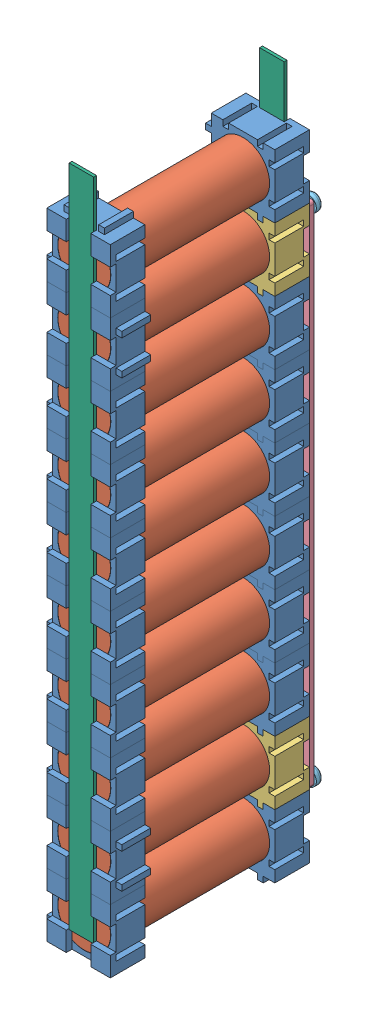
SolidWorks assembly 18650Module, configuration Default. Lengths in mm.
Overall size (26 239.99 73.08).
47 component instances, 6 part files, 28 mates.
Components (placement in the parent):
- BatteryWithCap-1: BatteryWithCap [Default] at (-119.8908 1.6761 1.2883) size (24 26 69)
  - EndCap-1: EndCap [Default] at (-3.9524 14.5628 21.4054) size (24 24 12)
  - HB2-1: HB2 [Default] at (-2.3515 12.807 21.4054) x (1 0 0) z (0 1 0) size (18.3 65.2 18.3)
  - EndCap-2: EndCap [Default] at (-3.9524 11.0511 86.4054) x (1 0 0) z (0 0 -1) size (24 24 12)
- BatteryWithCap-3: BatteryWithCap [Default] at (-119.8908 45.6761 1.2883) size (24 26 69)
  - EndCap-1: EndCap [Default] at (-3.9524 14.5628 21.4054) size (24 24 12)
  - HB2-1: HB2 [Default] at (-2.3515 12.807 21.4054) x (1 0 0) z (0 1 0) size (18.3 65.2 18.3)
  - EndCap-2: EndCap [Default] at (-3.9524 11.0511 86.4054) x (1 0 0) z (0 0 -1) size (24 24 12)
- BatteryWithCap-4: BatteryWithCap [Default] at (-119.8908 67.6761 1.2883) size (24 26 69)
  - EndCap-1: EndCap [Default] at (-3.9524 14.5628 21.4054) size (24 24 12)
  - HB2-1: HB2 [Default] at (-2.3515 12.807 21.4054) x (1 0 0) z (0 1 0) size (18.3 65.2 18.3)
  - EndCap-2: EndCap [Default] at (-3.9524 11.0511 86.4054) x (1 0 0) z (0 0 -1) size (24 24 12)
- BatteryWithCap-5: BatteryWithCap [Default] at (-119.8908 89.6761 1.2883) size (24 26 69)
  - EndCap-1: EndCap [Default] at (-3.9524 14.5628 21.4054) size (24 24 12)
  - HB2-1: HB2 [Default] at (-2.3515 12.807 21.4054) x (1 0 0) z (0 1 0) size (18.3 65.2 18.3)
  - EndCap-2: EndCap [Default] at (-3.9524 11.0511 86.4054) x (1 0 0) z (0 0 -1) size (24 24 12)
- BatteryWithCap-6: BatteryWithCap [Default] at (-119.8908 111.6761 1.2883) size (24 26 69)
  - EndCap-1: EndCap [Default] at (-3.9524 14.5628 21.4054) size (24 24 12)
  - HB2-1: HB2 [Default] at (-2.3515 12.807 21.4054) x (1 0 0) z (0 1 0) size (18.3 65.2 18.3)
  - EndCap-2: EndCap [Default] at (-3.9524 11.0511 86.4054) x (1 0 0) z (0 0 -1) size (24 24 12)
- BatteryWithCap-7: BatteryWithCap [Default] at (-119.8908 133.6761 1.2883) size (24 26 69)
  - EndCap-1: EndCap [Default] at (-3.9524 14.5628 21.4054) size (24 24 12)
  - HB2-1: HB2 [Default] at (-2.3515 12.807 21.4054) x (1 0 0) z (0 1 0) size (18.3 65.2 18.3)
  - EndCap-2: EndCap [Default] at (-3.9524 11.0511 86.4054) x (1 0 0) z (0 0 -1) size (24 24 12)
- BatteryWithCap-8: BatteryWithCap [Default] at (-119.8908 155.6761 1.2883) size (24 26 69)
  - EndCap-1: EndCap [Default] at (-3.9524 14.5628 21.4054) size (24 24 12)
  - HB2-1: HB2 [Default] at (-2.3515 12.807 21.4054) x (1 0 0) z (0 1 0) size (18.3 65.2 18.3)
  - EndCap-2: EndCap [Default] at (-3.9524 11.0511 86.4054) x (1 0 0) z (0 0 -1) size (24 24 12)
- BatteryWithCap-10: BatteryWithCap [Default] at (-119.8908 199.6761 1.2883) size (24 26 69)
  - EndCap-1: EndCap [Default] at (-3.9524 14.5628 21.4054) size (24 24 12)
  - HB2-1: HB2 [Default] at (-2.3515 12.807 21.4054) x (1 0 0) z (0 1 0) size (18.3 65.2 18.3)
  - EndCap-2: EndCap [Default] at (-3.9524 11.0511 86.4054) x (1 0 0) z (0 0 -1) size (24 24 12)
- ModuleWithM3EndCap-1: ModuleWithM3EndCap [Default] at (-93.9861 180.3782 17.4413) size (26 24.96 69)
  - EndCapWithM3-1: EndCapWithM3 [Default] at (-29.8572 11.8608 5.2524) size (24 24 12)
  - HB2-1: HB2 [Default] at (-28.2562 10.1049 70.2524) x (0.923728 0.383049 0) z (0.383049 -0.923728 0) size (18.3 65.2 18.3)
  - EndCap-1: EndCap [Default] at (-26.6553 11.8608 70.2524) x (-1 0 0) z (0 0 -1) size (24 24 12)
- ModuleWithM3EndCap-2: ModuleWithM3EndCap [Default] at (-93.9861 26.3782 17.4413) size (26 24.96 69)
  - EndCapWithM3-1: EndCapWithM3 [Default] at (-29.8572 11.8608 5.2524) size (24 24 12)
  - HB2-1: HB2 [Default] at (-28.2562 10.1049 70.2524) x (0.923728 0.383049 0) z (0.383049 -0.923728 0) size (18.3 65.2 18.3)
  - EndCap-1: EndCap [Default] at (-26.6553 11.8608 70.2524) x (-1 0 0) z (0 0 -1) size (24 24 12)
- DummyPCB-1: DummyPCB [Default] at (-97.7038 122.1138 19.0937) size (22 176 1.6)
- pan slot head_am-1: pan slot head_am [B18.6.7M - M3 x 0.5 x 6 Slotted PHMS --6N] at (-113.2423 27.4831 16.6937) x (0 0 1) z (-1 0 0) size (8.48 5.6 5.6)
- pan slot head_am-2: pan slot head_am [B18.6.7M - M3 x 0.5 x 6 Slotted PHMS --6N] at (-113.2423 199.4831 16.6937) x (0 0 1) z (-0.166536 0.986035 0) size (8.48 5.6 5.6)
- pan slot head_am-3: pan slot head_am [B18.6.7M - M3 x 0.5 x 6 Slotted PHMS --6N] at (-131.2423 199.4831 16.6937) x (0 0 1) z (0.381849 0.924225 0) size (8.48 5.6 5.6)
- pan slot head_am-4: pan slot head_am [B18.6.7M - M3 x 0.5 x 6 Slotted PHMS --6N] at (-131.2423 27.4831 16.6937) x (0 0 1) z (-1 0 0) size (8.48 5.6 5.6)
- CopperConductor-1: CopperConductor [Default] at (-122.6962 224.087 88.6937) size (8.5 230 1)
- CopperConductor-2: CopperConductor [Default] at (-122.6962 225.6736 22.6937) size (8.5 230 1)
Mates (geometry in assembly coordinates):
- Coincident20: coincident aligned: line of BatteryWithCap-3/EndCap-2 through (-133.2423 69.4831 77.6937) axis (0 0 1); line of BatteryWithCap-4/EndCap-2 through (-133.2423 69.4831 77.6937) axis (0 0 1)
- Coincident21: coincident anti-aligned: line of BatteryWithCap-3/EndCap-1 through (-129.2423 67.4831 32.6937) axis (1 0 0); line of BatteryWithCap-4/EndCap-1 through (-127.2423 67.4831 32.6937) axis (-1 0 0)
- Coincident22: coincident aligned: line of BatteryWithCap-4/EndCap-2 through (-133.2423 91.4831 77.6937) axis (0 0 1); line of BatteryWithCap-5/EndCap-2 through (-133.2423 91.4831 77.6937) axis (0 0 1)
- Coincident24: coincident anti-aligned: line of BatteryWithCap-4/EndCap-1 through (-129.2423 89.4831 32.6937) axis (1 0 0); line of BatteryWithCap-5/EndCap-1 through (-127.2423 89.4831 32.6937) axis (-1 0 0)
- Coincident25: coincident aligned: line of BatteryWithCap-5/EndCap-2 through (-133.2423 113.4831 77.6937) axis (0 0 1); line of BatteryWithCap-6/EndCap-2 through (-133.2423 113.4831 77.6937) axis (0 0 1)
- Coincident26: coincident anti-aligned: line of BatteryWithCap-6/EndCap-1 through (-127.2423 111.4831 32.6937) axis (-1 0 0); line of BatteryWithCap-5/EndCap-1 through (-129.2423 111.4831 32.6937) axis (1 0 0)
- Coincident27: coincident aligned: line of BatteryWithCap-6/EndCap-2 through (-133.2423 135.4831 77.6937) axis (0 0 1); line of BatteryWithCap-7/EndCap-2 through (-133.2423 135.4831 77.6937) axis (0 0 1)
- Coincident28: coincident anti-aligned: line of BatteryWithCap-6/EndCap-1 through (-129.2423 133.4831 32.6937) axis (1 0 0); line of BatteryWithCap-7/EndCap-1 through (-127.2423 133.4831 32.6937) axis (-1 0 0)
- Coincident29: coincident aligned: line of BatteryWithCap-7/EndCap-2 through (-133.2423 157.4831 77.6937) axis (0 0 1); line of BatteryWithCap-8/EndCap-2 through (-133.2423 157.4831 77.6937) axis (0 0 1)
- Coincident30: coincident anti-aligned: line of BatteryWithCap-7/EndCap-1 through (-129.2423 155.4831 32.6937) axis (1 0 0); line of BatteryWithCap-8/EndCap-1 through (-127.2423 155.4831 32.6937) axis (-1 0 0)
- Coincident31: coincident aligned: line of BatteryWithCap-1/EndCap-2 through (-133.2423 25.4831 77.6937) axis (0 0 1); line of ModuleWithM3EndCap-2/EndCap-1 through (-133.2423 25.4831 77.6937) axis (0 0 1)
- Coincident32: coincident anti-aligned: line of BatteryWithCap-1/EndCap-2 through (-126.4923 25.4831 89.6937) axis (-1 0 0); line of ModuleWithM3EndCap-2/EndCap-1 through (-133.2423 25.4831 89.6937) axis (1 0 0)
- Coincident33: coincident aligned: line of BatteryWithCap-3/EndCap-2 through (-133.2423 47.4831 77.6937) axis (0 0 1); line of ModuleWithM3EndCap-2/EndCap-1 through (-133.2423 47.4831 77.6937) axis (0 0 1)
- Coincident34: coincident anti-aligned: line of BatteryWithCap-3/EndCap-2 through (-133.2423 47.4831 89.6937) axis (1 0 0); line of ModuleWithM3EndCap-2/EndCap-1 through (-126.4923 47.4831 89.6937) axis (-1 0 0)
- Coincident35: coincident aligned: line of BatteryWithCap-8/EndCap-1 through (-133.2423 179.4831 32.6937) axis (0 0 -1); line of ModuleWithM3EndCap-1/EndCapWithM3-1 through (-133.2423 179.4831 32.6937) axis (0 0 -1)
- Coincident36: coincident anti-aligned: line of BatteryWithCap-8/EndCap-1 through (-133.2423 179.4831 20.6937) axis (1 0 0); line of ModuleWithM3EndCap-1/EndCapWithM3-1 through (-126.4923 179.4831 20.6937) axis (-1 0 0)
- Coincident37: coincident aligned: line of BatteryWithCap-10/EndCap-2 through (-133.2423 201.4831 77.6937) axis (0 0 1); line of ModuleWithM3EndCap-1/EndCap-1 through (-133.2423 201.4831 77.6937) axis (0 0 1)
- Coincident38: coincident anti-aligned: line of BatteryWithCap-10/EndCap-2 through (-133.2423 201.4831 89.6937) axis (1 0 0); line of ModuleWithM3EndCap-1/EndCap-1 through (-126.4923 201.4831 89.6937) axis (-1 0 0)
- Coincident39: coincident anti-aligned: line of ModuleWithM3EndCap-1/EndCapWithM3-1 through (-111.2423 201.4831 20.6937) axis (0 -1 0); line of DummyPCB-1 through (-111.2423 26.4831 20.6937) axis (0 1 0)
- Coincident40: coincident anti-aligned: line of ModuleWithM3EndCap-1/EndCapWithM3-1 through (-133.2423 201.4831 20.6937) axis (1 0 0); line of DummyPCB-1 through (-112.2423 201.4831 20.6937) axis (-1 0 0)
- Coincident41: coincident anti-aligned: circle of DummyPCB-1; circle of pan slot head_am-2
- Coincident42: coincident anti-aligned: circle of DummyPCB-1; circle of pan slot head_am-3
- Coincident43: coincident anti-aligned: circle of DummyPCB-1; circle of pan slot head_am-1
- Coincident44: coincident anti-aligned: circle of DummyPCB-1; circle of pan slot head_am-4
- Coincident45: coincident anti-aligned: plane of ModuleWithM3EndCap-2/EndCap-1 through (-126.4923 25.4831 89.6937) normal (1 0 0); plane of CopperConductor-1 through (-126.4923 239.8904 87.6937) normal (-1 0 0)
- Coincident46: coincident anti-aligned: plane of BatteryWithCap-1/HB2-1 through (-122.2423 14.4831 87.6937) normal (0 0 1); plane of CopperConductor-1 through (-122.6962 224.087 87.6937) normal (0 0 -1)
- Coincident47: coincident anti-aligned: plane of BatteryWithCap-1/HB2-1 through (-122.2423 14.4831 22.6937) normal (0 0 -1); plane of CopperConductor-2 through (-122.6962 225.6736 22.6937) normal (0 0 1)
- Coincident48: coincident anti-aligned: plane of BatteryWithCap-1/EndCap-1 through (-126.4923 25.4831 20.6937) normal (1 0 0); plane of CopperConductor-2 through (-126.4923 241.477 21.6937) normal (-1 0 0)
